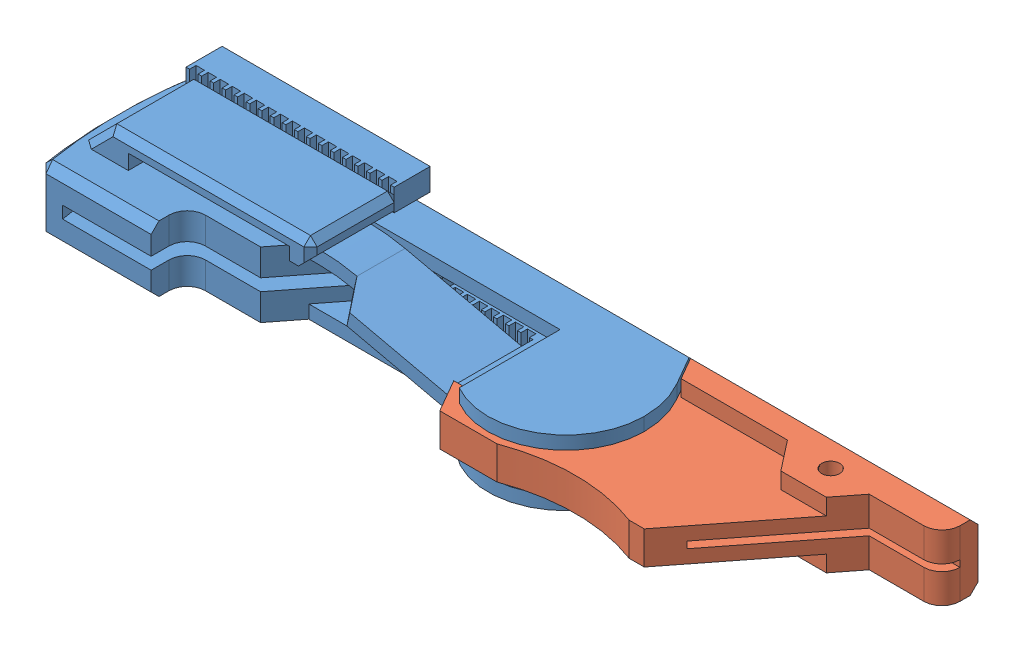
SolidWorks assembly EAB3, configuration Default. Lengths in mm.
Overall size (130.5 15.61 27).
2 component instances, 2 part files, 3 mates.
Components (placement in the parent):
- EAB3_Body-1: EAB3_Body [Default] at origin size (88.5 15.61 27)
- EAB3_BladeHolder-1: EAB3_BladeHolder [Default] x (-1 0 0) z (0 0 1) size (65.68 10.9 27)
Mates (geometry in assembly coordinates):
- Concentric1: concentric aligned: cylinder of EAB3_Body-1 through (0 -9.5525 0) axis (0 1 0) radius 3.5; cylinder of EAB3_BladeHolder-1 through (0 -2.75 0) axis (0 1 0) radius 4
- Coincident1: coincident anti-aligned: plane of EAB3_Body-1 through (0 0 0) normal (0 1 0); plane of EAB3_BladeHolder-1
- Angle1: planar angle = 0 rad aligned: plane of EAB3_Body-1 through (0 0 0) normal (0 0 1); plane of EAB3_BladeHolder-1 through (0 0 0) normal (0 0 1)
